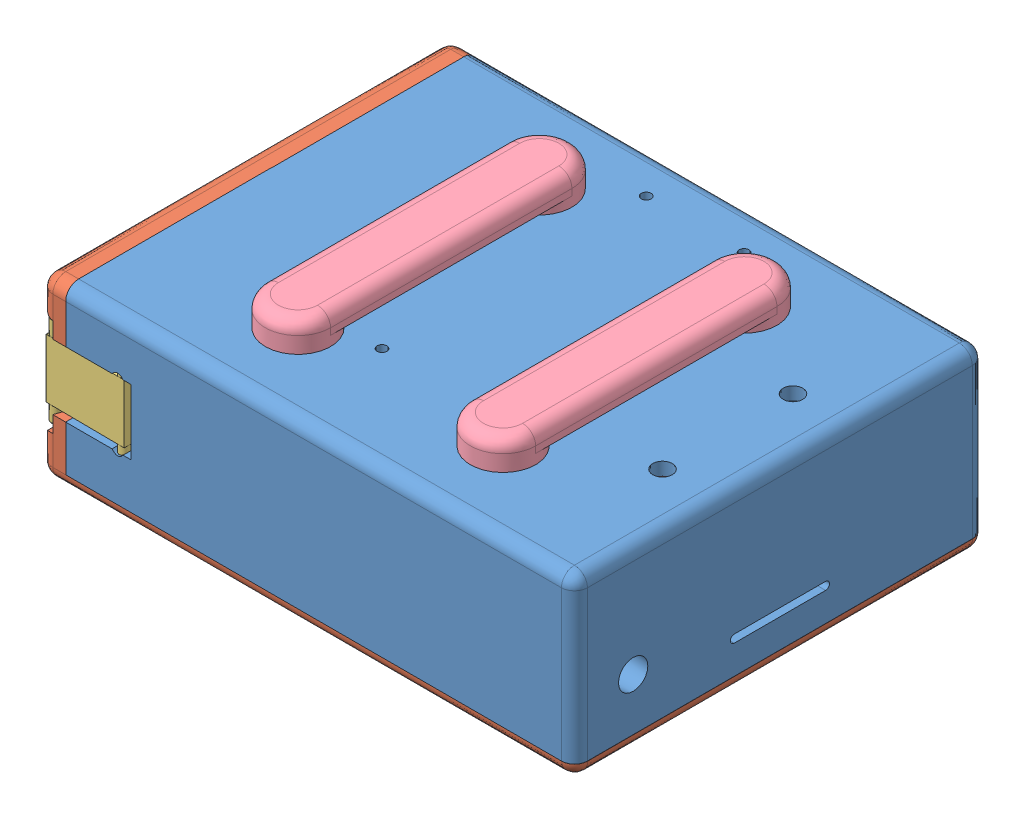
SolidWorks assembly Flexiforce Box, configuration Default. Lengths in mm.
Overall size (82 31.5 63).
8 component instances, 6 part files, 10 mates.
Components (placement in the parent):
- Flexiforce box-1: Flexiforce box [Default] at (15.3662 34.7679 72.358) size (78 25 63)
- Flexi Force Box Lid-1: Flexi Force Box Lid [Default] at (13.4009 34.7679 9.358) x (0 -1 0) z (0 0 1) size (27 82 63)
- Box Locking Part-2: Box Locking Part [Default] at (26.0695 42.5551 72.0924) x (-0.999962 0 -0.008727) z (0 -1 0) size (12.2 1.5 14)
- Box Locking Part-3: Box Locking Part [Default] at (26.1306 42.1679 11.5027) x (-1 0 0) z (0 -1 0) size (12.2 1.5 14)
- Strap holders-1: Strap holders [Default] at (72.0623 64.2679 60.0021) x (-1 0 0) z (0 0 1) size (10 4.5 47)
- Strap holders-2: Strap holders [Default] at (40.6649 64.2679 23.0384) x (1 0 0) z (0 0 -1) size (10 4.5 47)
- 9V-battery-1: 9V-battery [Default] at (11.7477 57.7679 102.3062) x (-1 0 0) z (0 -1 0) size (26.04 47.88 17.14)
- Arduino Nano 33 IoT-1: Arduino Nano 33 IoT [Default] at (57.2462 56.9679 36.588) x (1 0 0) z (0 0 -1) size (17.78 5.55 45.32)
Mates (geometry in assembly coordinates):
- Coincident1: coincident anti-aligned: plane of Flexiforce box-1 through (15.3662 34.7679 72.358) normal (0 -1 0); plane of Flexi Force Box Lid-1 through (95.4009 34.7679 72.358) normal (0 1 0)
- Parallel1: parallel aligned: plane of Flexiforce box-1 through (15.3662 59.7679 9.358) normal (0 0 -1); plane of Flexi Force Box Lid-1 through (17.4009 34.7679 9.358) normal (0 0 -1)
- Coincident2: coincident aligned: plane of Flexiforce box-1 through (15.3662 59.7679 72.358) normal (0 0 1); plane of Flexi Force Box Lid-1 through (17.4009 34.7679 72.358) normal (0 0 1)
- Coincident3: coincident anti-aligned: plane of Flexiforce box-1 through (15.3662 59.7679 72.358) normal (0 1 0); plane of Strap holders-1 through (72.0623 59.7679 60.0021) normal (0 -1 0)
- Coincident4: coincident anti-aligned: plane of Flexiforce box-1 through (15.3662 59.7679 72.358) normal (0 1 0); plane of Strap holders-2 through (40.6649 59.7679 60.0384) normal (0 -1 0)
- Coincident5: coincident anti-aligned: plane of Flexiforce box-1 through (15.3662 57.7679 72.358) normal (0 -1 0); plane of 9V-battery-1 through (31.8487 57.7679 33.846) normal (0 1 0)
- Coincident6: coincident anti-aligned: plane of Flexiforce box-1 through (17.3662 57.7679 13.358) normal (0 0 1); plane of 9V-battery-1 through (43.3422 41.3849 13.358) normal (0 0 -1)
- Coincident7: coincident anti-aligned: plane of Flexiforce box-1 through (44.8662 47.7679 68.358) normal (-1 0 0); plane of 9V-battery-1 through (44.8662 49.0179 33.846) normal (1 0 0)
- Concentric1: concentric aligned: circle of Flexiforce box-1; cylinder of Arduino Nano 33 IoT-1 through (64.8662 103.6515 15.858) axis (0 -1 0) radius 0.8
- Coincident9: coincident anti-aligned: plane of Flexiforce box-1 through (15.3662 57.7679 72.358) normal (0 -1 0); plane of Arduino Nano 33 IoT-1 through (57.2462 57.7679 36.588) normal (0 1 0)
